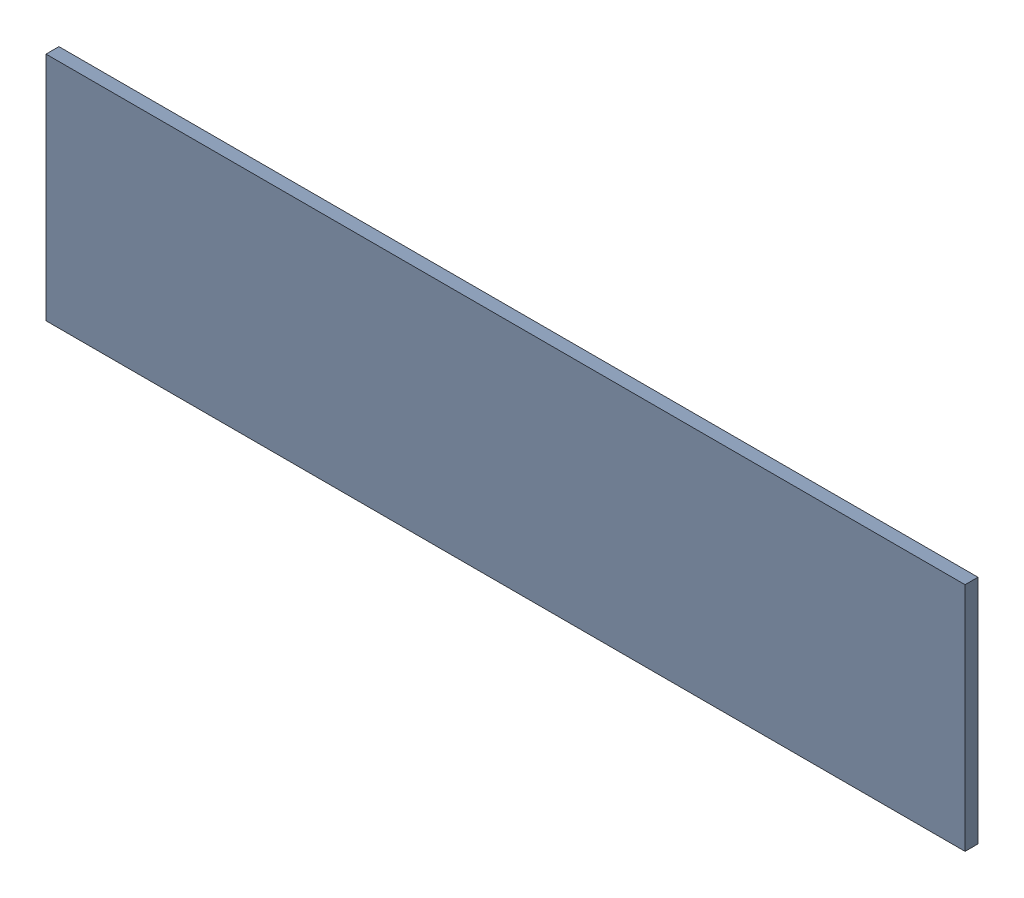
SolidWorks assembly 6327396352, configuration Default. Lengths in mm.
Overall size (1.8 0.45 0.03).
2 component instances, 1 part files, 0 mates.
Components (placement in the parent):
- 6701982208-1:  [Default] at (27.7 14.8 0) (suppressed, hidden)
- Extruded-24-1: Extruded-24 [Default] at origin size (1.8 0.45 0.03)
